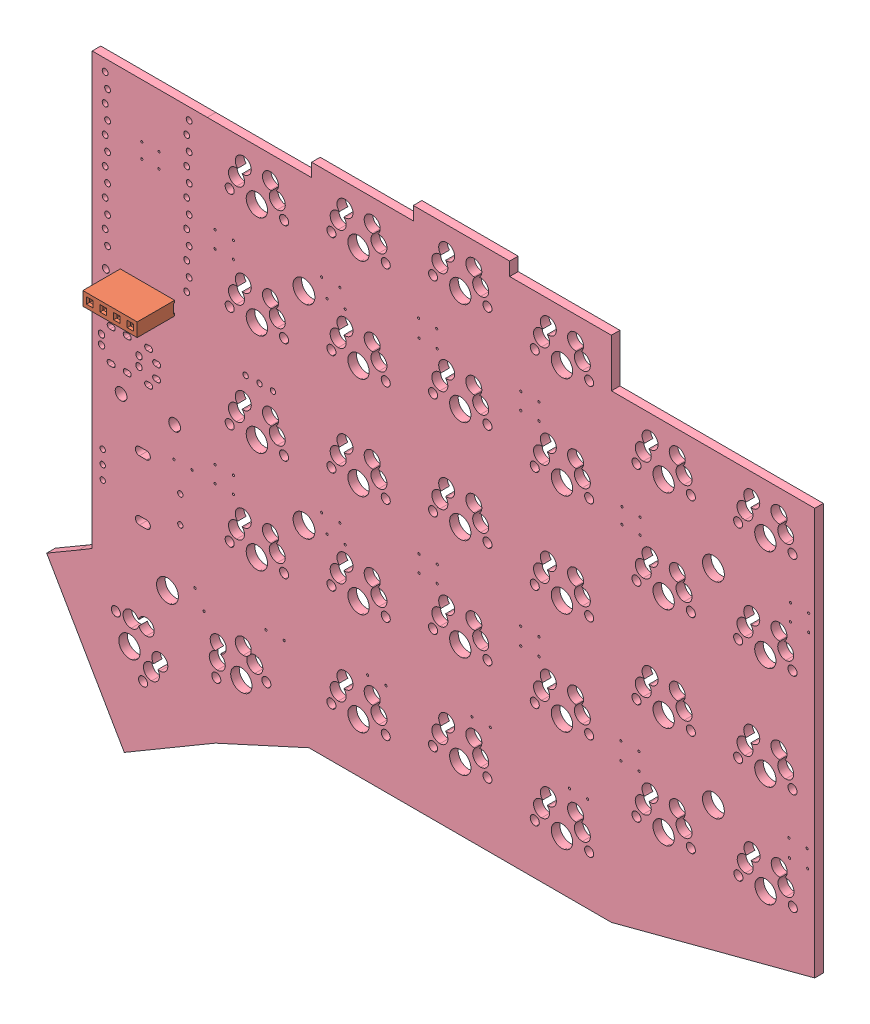
SolidWorks assembly SofleKeyboard, configuration По умолчанию. Lengths in mm.
Overall size (143.5 115.5 10.1).
68 component instances, 4 part files, 0 mates.
Components (placement in the parent):
- SofleKeyboard.step-1: SofleKeyboard.step [По умолчанию] at origin size (143.5 115.5 10.1)
  - D_SOD-123.step-1: D_SOD-123.step [По умолчанию] at (24.67 -17.448 -0.05) x (1 0 0) z (0 0 -1) size (3.8 1.6 1.25)
    - D_SOD_123.step-1: D_SOD_123.step [По умолчанию] at origin size (3.8 1.6 1.25)
  - D_SOD-123.step-2: D_SOD-123.step [По умолчанию] at (44.57 -15.148 -0.05) x (1 0 0) z (0 0 -1) size (3.8 1.6 1.25)
    - D_SOD_123.step-1: D_SOD_123.step [По умолчанию] at origin size (3.8 1.6 1.25)
  - D_SOD-123.step-3: D_SOD-123.step [По умолчанию] at (62.67 -12.748 -0.05) x (1 0 0) z (0 0 -1) size (3.8 1.6 1.25)
    - D_SOD_123.step-1: D_SOD_123.step [По умолчанию] at origin size (3.8 1.6 1.25)
  - D_SOD-123.step-4: D_SOD-123.step [По умолчанию] at (81.77 -15.048 -0.05) x (1 0 0) z (0 0 -1) size (3.8 1.6 1.25)
    - D_SOD_123.step-1: D_SOD_123.step [По умолчанию] at origin size (3.8 1.6 1.25)
  - D_SOD-123.step-5: D_SOD-123.step [По умолчанию] at (100.67 -24.248 -0.05) x (1 0 0) z (0 0 -1) size (3.8 1.6 1.25)
    - D_SOD_123.step-1: D_SOD_123.step [По умолчанию] at origin size (3.8 1.6 1.25)
  - D_SOD-123.step-6: D_SOD-123.step [По умолчанию] at (132.17 -24.048 -0.05) x (1 0 0) z (0 0 -1) size (3.8 1.6 1.25)
    - D_SOD_123.step-1: D_SOD_123.step [По умолчанию] at origin size (3.8 1.6 1.25)
  - D_SOD-123.step-7: D_SOD-123.step [По умолчанию] at (24.67 -20.548 -0.05) x (1 0 0) z (0 0 -1) size (3.8 1.6 1.25)
    - D_SOD_123.step-1: D_SOD_123.step [По умолчанию] at origin size (3.8 1.6 1.25)
  - D_SOD-123.step-8: D_SOD-123.step [По умолчанию] at (45.57 -18.148 -0.05) x (1 0 0) z (0 0 -1) size (3.8 1.6 1.25)
    - D_SOD_123.step-1: D_SOD_123.step [По умолчанию] at origin size (3.8 1.6 1.25)
  - D_SOD-123.step-9: D_SOD-123.step [По умолчанию] at (62.77 -15.948 -0.05) x (1 0 0) z (0 0 -1) size (3.8 1.6 1.25)
    - D_SOD_123.step-1: D_SOD_123.step [По умолчанию] at origin size (3.8 1.6 1.25)
  - D_SOD-123.step-10: D_SOD-123.step [По умолчанию] at (81.77 -18.148 -0.05) x (1 0 0) z (0 0 -1) size (3.8 1.6 1.25)
    - D_SOD_123.step-1: D_SOD_123.step [По умолчанию] at origin size (3.8 1.6 1.25)
  - D_SOD-123.step-11: D_SOD-123.step [По умолчанию] at (100.67 -27.148 -0.05) x (1 0 0) z (0 0 -1) size (3.8 1.6 1.25)
    - D_SOD_123.step-1: D_SOD_123.step [По умолчанию] at origin size (3.8 1.6 1.25)
  - D_SOD-123.step-12: D_SOD-123.step [По умолчанию] at (132.17 -27.148 -0.05) x (1 0 0) z (0 0 -1) size (3.8 1.6 1.25)
    - D_SOD_123.step-1: D_SOD_123.step [По умолчанию] at origin size (3.8 1.6 1.25)
  - D_SOD-123.step-13: D_SOD-123.step [По умолчанию] at (24.67 -55.448 -0.05) x (1 0 0) z (0 0 -1) size (3.8 1.6 1.25)
    - D_SOD_123.step-1: D_SOD_123.step [По умолчанию] at origin size (3.8 1.6 1.25)
  - D_SOD-123.step-14: D_SOD-123.step [По умолчанию] at (44.57 -53.248 -0.05) x (1 0 0) z (0 0 -1) size (3.8 1.6 1.25)
    - D_SOD_123.step-1: D_SOD_123.step [По умолчанию] at origin size (3.8 1.6 1.25)
  - D_SOD-123.step-15: D_SOD-123.step [По умолчанию] at (62.77 -50.848 -0.05) x (1 0 0) z (0 0 -1) size (3.8 1.6 1.25)
    - D_SOD_123.step-1: D_SOD_123.step [По умолчанию] at origin size (3.8 1.6 1.25)
  - D_SOD-123.step-16: D_SOD-123.step [По умолчанию] at (81.77 -53.048 -0.05) x (1 0 0) z (0 0 -1) size (3.8 1.6 1.25)
    - D_SOD_123.step-1: D_SOD_123.step [По умолчанию] at origin size (3.8 1.6 1.25)
  - D_SOD-123.step-17: D_SOD-123.step [По умолчанию] at (100.47 -62.248 -0.05) x (1 0 0) z (0 0 -1) size (3.8 1.6 1.25)
    - D_SOD_123.step-1: D_SOD_123.step [По умолчанию] at origin size (3.8 1.6 1.25)
  - D_SOD-123.step-18: D_SOD-123.step [По умолчанию] at (131.87 -62.248 -0.05) x (1 0 0) z (0 0 -1) size (3.8 1.6 1.25)
    - D_SOD_123.step-1: D_SOD_123.step [По умолчанию] at origin size (3.8 1.6 1.25)
  - D_SOD-123.step-19: D_SOD-123.step [По умолчанию] at (24.67 -58.548 -0.05) x (1 0 0) z (0 0 -1) size (3.8 1.6 1.25)
    - D_SOD_123.step-1: D_SOD_123.step [По умолчанию] at origin size (3.8 1.6 1.25)
  - D_SOD-123.step-20: D_SOD-123.step [По умолчанию] at (45.57 -56.248 -0.05) x (1 0 0) z (0 0 -1) size (3.8 1.6 1.25)
    - D_SOD_123.step-1: D_SOD_123.step [По умолчанию] at origin size (3.8 1.6 1.25)
  - D_SOD-123.step-21: D_SOD-123.step [По умолчанию] at (62.77 -53.948 -0.05) x (1 0 0) z (0 0 -1) size (3.8 1.6 1.25)
    - D_SOD_123.step-1: D_SOD_123.step [По умолчанию] at origin size (3.8 1.6 1.25)
  - D_SOD-123.step-22: D_SOD-123.step [По умолчанию] at (81.77 -56.248 -0.05) x (1 0 0) z (0 0 -1) size (3.8 1.6 1.25)
    - D_SOD_123.step-1: D_SOD_123.step [По умолчанию] at origin size (3.8 1.6 1.25)
  - D_SOD-123.step-23: D_SOD-123.step [По умолчанию] at (100.47 -65.448 -0.05) x (1 0 0) z (0 0 -1) size (3.8 1.6 1.25)
    - D_SOD_123.step-1: D_SOD_123.step [По умолчанию] at origin size (3.8 1.6 1.25)
  - D_SOD-123.step-24: D_SOD-123.step [По умолчанию] at (131.97 -65.448 -0.05) x (1 0 0) z (0 0 -1) size (3.8 1.6 1.25)
    - D_SOD_123.step-1: D_SOD_123.step [По умолчанию] at origin size (3.8 1.6 1.25)
  - D_SOD-123.step-25: D_SOD-123.step [По умолчанию] at (16.97 -58.458 -0.05) x (1 0 0) z (0 0 -1) size (3.8 1.6 1.25)
    - D_SOD_123.step-1: D_SOD_123.step [По умолчанию] at origin size (3.8 1.6 1.25)
  - D_SOD-123.step-26: D_SOD-123.step [По умолчанию] at (20.07 -78.748 -0.05) x (0.5 -0.866025 0) z (0 0 -1) size (3.8 1.6 1.25)
    - D_SOD_123.step-1: D_SOD_123.step [По умолчанию] at origin size (3.8 1.6 1.25)
  - D_SOD-123.step-27: D_SOD-123.step [По умолчанию] at (34.17 -77.448 -0.05) x (1 0 0) z (0 0 -1) size (3.8 1.6 1.25)
    - D_SOD_123.step-1: D_SOD_123.step [По умолчанию] at origin size (3.8 1.6 1.25)
  - D_SOD-123.step-28: D_SOD-123.step [По умолчанию] at (53.17 -75.248 -0.05) x (1 0 0) z (0 0 -1) size (3.8 1.6 1.25)
    - D_SOD_123.step-1: D_SOD_123.step [По умолчанию] at origin size (3.8 1.6 1.25)
  - D_SOD-123.step-29: D_SOD-123.step [По умолчанию] at (72.67 -72.258 -0.05) x (1 0 0) z (0 0 -1) size (3.8 1.6 1.25)
    - D_SOD_123.step-1: D_SOD_123.step [По умолчанию] at origin size (3.8 1.6 1.25)
  - PinSocket_1x04_P2.54mm_Vertical.step-1: PinSocket_1x04_P2.54mm_Vertical.step [По умолчанию] at (6.57 -33.858 1.65) x (0 1 0) z (0 0 1) size (2.54 10.16 10.1)
    - PinSocket_1x04_P254mm_Vertical.step-1: PinSocket_1x04_P254mm_Vertical.step [По умолчанию] at origin size (2.54 10.16 10.1)
  - D_SOD-123.step-30: D_SOD-123.step [По умолчанию] at (90.87 -74.758 -0.05) x (1 0 0) z (0 0 -1) size (3.8 1.6 1.25)
    - D_SOD_123.step-1: D_SOD_123.step [По умолчанию] at origin size (3.8 1.6 1.25)
  - R_1206_3216Metric.step-1: R_1206_3216Metric.step [По умолчанию] at (12.47 -11.458 -0.05) x (0 -1 0) z (0 0 -1) size (3.2 1.6 0.55)
    - R_1206_3216Metric-0.step-1: R_1206_3216Metric-0.step [По умолчанию] at origin size (3.2 1.6 0.55)
  - R_1206_3216Metric.step-2: R_1206_3216Metric.step [По умолчанию] at (9.27 -11.458 -0.05) x (0 -1 0) z (0 0 -1) size (3.2 1.6 0.55)
    - R_1206_3216Metric-0.step-1: R_1206_3216Metric-0.step [По умолчанию] at origin size (3.2 1.6 0.55)
  - _autosave-SofleKeyboard_PCB.step-1: _autosave-SofleKeyboard_PCB.step [По умолчанию] at origin size (143.5 115.5 1.6)
